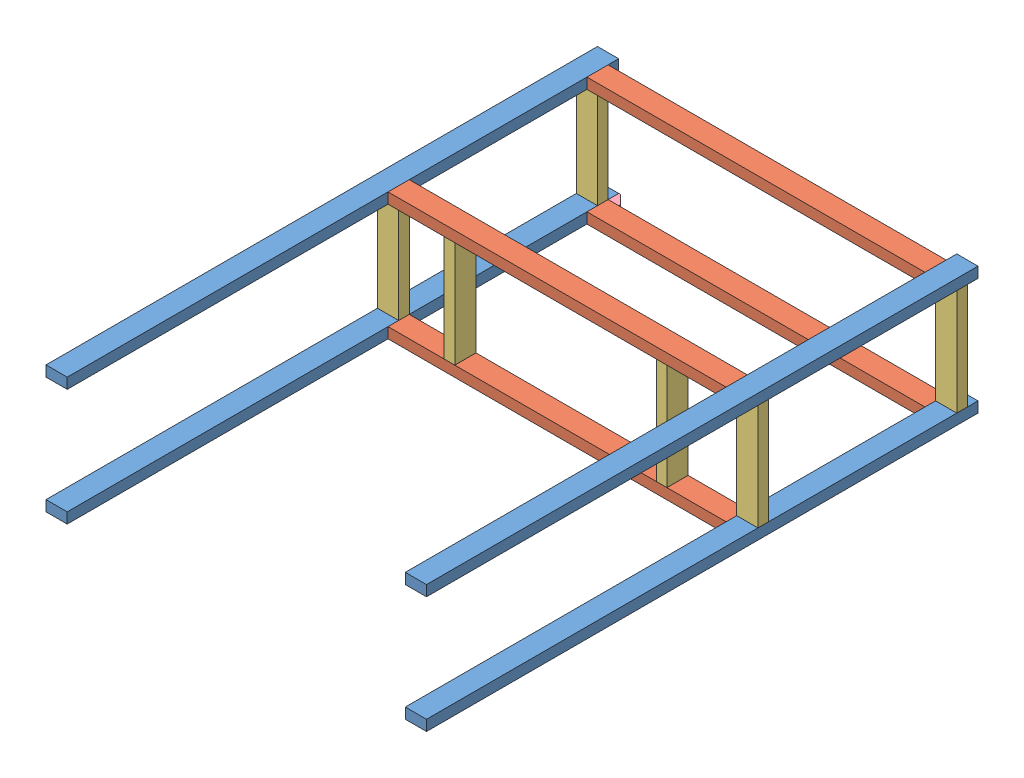
SolidWorks assembly cnc_frame, configuration Default. Lengths in mm.
Overall size (1435 480 2080).
15 component instances, 4 part files, 14 mates.
Components (placement in the parent):
- vert-1: vert [Default] at (791.2019 1253.9186 498.8325) size (80 40 2080)
- vert-2: vert [Default] at (791.2019 1693.9186 498.8325) size (80 40 2080)
- vert-3: vert [Default] at (-563.7981 1253.9186 498.8325) size (80 40 2080)
- vert-4: vert [Default] at (-563.7981 1693.9186 498.8325) size (80 40 2080)
- hor-1: hor [Default] at (767.2921 1693.9186 1312.7422) x (0 0 1) z (-1 0 0) size (80 40 1275)
- hor-2: hor [Default] at (767.2921 1693.9186 562.7422) x (0 0 1) z (-1 0 0) size (80 40 1275)
- hor-3: hor [Default] at (767.2921 1253.9186 1312.7422) x (0 0 1) z (-1 0 0) size (80 40 1275)
- hor-4: hor [Default] at (767.2921 1253.9186 562.7422) x (0 0 1) z (-1 0 0) size (80 40 1275)
- per-1: per [Default] at (-563.7981 1276.5501 561.4641) x (1 0 0) z (0 1 0) size (80 40 400)
- per-2: per [Default] at (791.2019 1276.5501 561.4641) x (1 0 0) z (0 1 0) size (80 40 400)
- per-3: per [Default] at (-563.7981 1276.5501 1311.4641) x (1 0 0) z (0 1 0) size (80 40 400)
- per-4: per [Default] at (791.2019 1276.5501 1311.4641) x (1 0 0) z (0 1 0) size (80 40 400)
- per-5: per [Default] at (-273.4001 1276.5501 1344.9227) x (0 0 -1) z (0 1 0) size (80 40 400)
- per-6: per [Default] at (526.5999 1276.5501 1344.9227) x (0 0 -1) z (0 1 0) size (80 40 400)
- force_angle-1: force_angle [Default] at (-510.4842 1254.1851 538.8325) x (-1 0 0) z (0 0 -1) size (40 40 40)
Mates (geometry in assembly coordinates):
- Совпадение1: coincident aligned: plane of vert-4 through (-587.7079 1716.5501 2578.8325) normal (0 1 0); plane of hor-1 through (-507.7079 1716.5501 1288.8325) normal (0 1 0)
- Совпадение2: coincident anti-aligned: plane of vert-4 through (-507.7079 1716.5501 2578.8325) normal (1 0 0); plane of hor-1 through (-507.7079 1693.9186 1312.7422) normal (-1 0 0)
- Расстояние1: distance = 40 mm aligned: plane of hor-2 through (-507.7079 1716.5501 538.8325) normal (0 0 -1); plane of vert-4 through (-563.7981 1693.9186 498.8325) normal (0 0 -1)
- Совпадение4: coincident anti-aligned: plane of vert-3 through (-587.7079 1276.5501 2578.8325) normal (0 1 0); plane of per-1 through (-563.7981 1276.5501 561.4641) normal (0 -1 0)
- Совпадение5: coincident aligned: plane of vert-3 through (-587.7079 1276.5501 2578.8325) normal (-1 0 0); plane of per-1 through (-587.7079 1676.5501 538.8325) normal (-1 0 0)
- Расстояние2: distance = 40 mm aligned: plane of vert-3 through (-563.7981 1253.9186 498.8325) normal (0 0 -1); plane of per-1 through (-587.7079 1676.5501 538.8325) normal (0 0 -1)
- Совпадение7: coincident aligned: plane of hor-1 through (-507.7079 1716.5501 1288.8325) normal (0 0 -1); plane of per-5 through (-296.0317 1676.5501 1288.8325) normal (0 0 -1)
- Совпадение8: coincident anti-aligned: plane of hor-1 through (-507.7079 1676.5501 1288.8325) normal (0 -1 0); plane of per-5 through (-273.4001 1676.5501 1344.9227) normal (0 1 0)
- Совпадение9: coincident anti-aligned: plane of vert-4 through (-587.7079 1676.5501 2578.8325) normal (0 -1 0); plane of per-7 through (-570.3395 1676.5501 2514.9227) normal (0 1 0)
- Совпадение10: coincident aligned: plane of vert-4 through (-587.7079 1716.5501 2578.8325) normal (-1 0 0); plane of per-7 through (-587.7079 1276.5501 2538.8325) normal (-1 0 0)
- Расстояние3: distance = 40 mm aligned: plane of per-7 through (-547.7079 1276.5501 2538.8325) normal (0 0 1); plane of vert-4 through (-563.7981 1693.9186 2578.8325) normal (0 0 1)
- Совпадение13: coincident anti-aligned: plane of hor-4 through (-507.7079 1276.5501 538.8325) normal (0 0 -1); plane of force_angle-1 through (-510.4842 1254.1851 538.8325) normal (0 0 1)
- Совпадение14: coincident anti-aligned: plane of vert-3 through (-507.7079 1276.5501 2578.8325) normal (1 0 0); plane of force_angle-1 through (-507.7079 1254.1851 541.6088) normal (-1 0 0)
- Совпадение15: coincident aligned: plane of hor-4 through (-507.7079 1276.5501 538.8325) normal (0 1 0); plane of force_angle-1 through (-467.7079 1276.5501 532.8325) normal (0 1 0)
